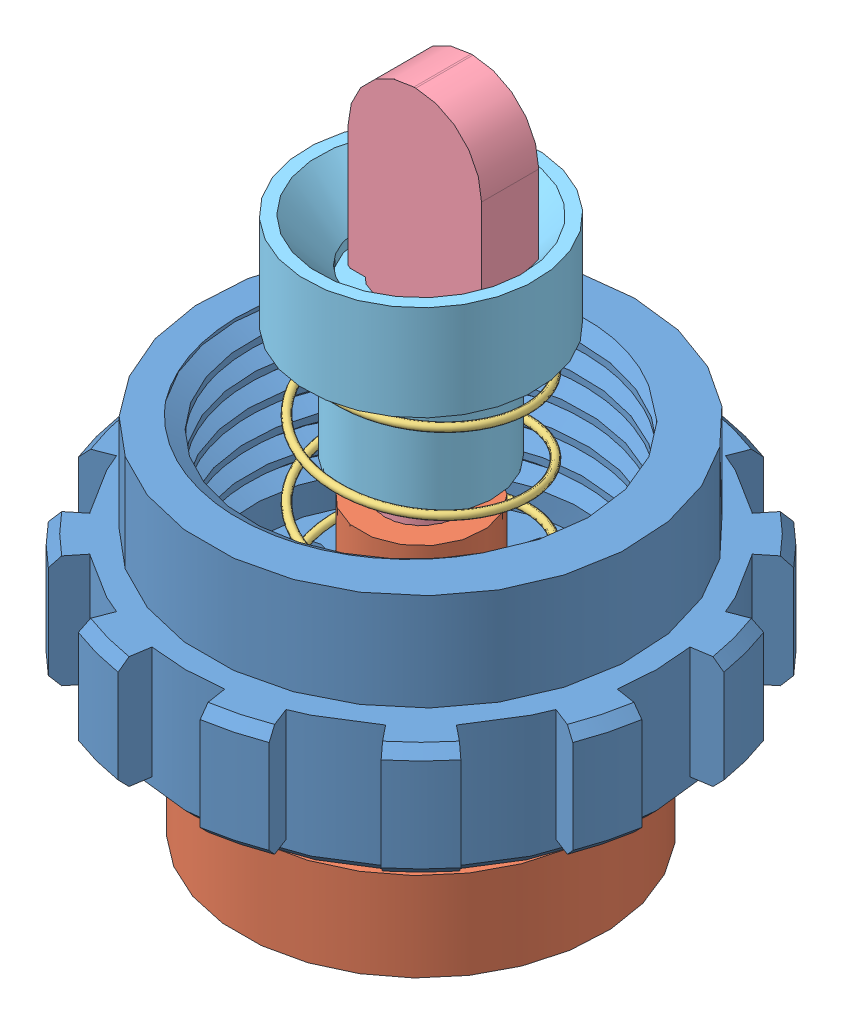
SolidWorks assembly Assy_Pressure_Relief_Valve, configuration Default. Lengths in mm.
Overall size (27.47 35.1 27.47).
5 component instances, 5 part files, 8 mates.
Components (placement in the parent):
- Pressure Relief Valve Body-1: Pressure Relief Valve Body [Default] at origin size (27.47 12.53 27.47)
- Pressure Relief Valve Pop_Up-1: Pressure Relief Valve Pop_Up [Default] at (0 -6.6 0) size (18.9 15.2 18.9)
- Pressure Relief Valve Spring-1: Pressure Relief Valve Spring [Default] at (0 2.3 0) size (10.63 15.06 10.73)
- Pressure Relief Valve Pin Center-1: Pressure Relief Valve Pin Center [Default] at (0 3.6 0) size (7.5 24.9 5.65)
- Pressure Relief Valve Seal-1: Pressure Relief Valve Seal [Default] at (0 10.4 0) x (0.927686 0 -0.373362) z (0.373362 0 0.927686) size (12 11 12)
Mates (geometry in assembly coordinates):
- Concentric1: concentric: cylinder of assembly; cylinder of assembly; cylinder of Pressure Relief Valve Body-1 through (0 -7.7 0) axis (0 1 0) radius 3.5; cylinder of Pressure Relief Valve Pop_Up-1 through (0 -6.6 0) axis (0 -1 0) radius 3.19
- Distance1: distance = 0 mm: plane of assembly; plane of assembly; plane of Pressure Relief Valve Pop_Up-1 through (5.25 0 0) normal (0 1 0); plane of Pressure Relief Valve Body-1 through (0 0 0) normal (0 -1 0)
- Coincident1: coincident: plane of assembly; plane of assembly; plane of Pressure Relief Valve Body-1 through (8.75 2.3 0) normal (0 1 0); plane of Pressure Relief Valve Spring-1 through (0 2.3 0) normal (0 1 0)
- Concentric2: concentric: cylinder of assembly; line of assembly; cylinder of Pressure Relief Valve Pop_Up-1 through (0 -6.6 0) axis (0 -1 0) radius 1.9; line of Pressure Relief Valve Spring-1 through (100 0 52.3) axis (0 0 -1)
- Coincident2: coincident: plane of assembly; plane of assembly; plane of Pressure Relief Valve Pop_Up-1 through (1.9 3.6 0) normal (0 1 0); plane of Pressure Relief Valve Pin Center-1 through (0 3.6 0) normal (0 -1 0)
- Concentric3: concentric: cylinder of assembly; cylinder of assembly; cylinder of Pressure Relief Valve Pop_Up-1 through (0 -6.6 0) axis (0 -1 0) radius 1.9; cylinder of Pressure Relief Valve Pin Center-1 through (0 3.6 0) axis (0 -1 0) radius 1.9
- Concentric4: concentric: cylinder of assembly; cylinder of assembly; cylinder of Pressure Relief Valve Pin Center-1 through (0 3.6 0) axis (0 -1 0) radius 1.9; cylinder of Pressure Relief Valve Seal-1 through (0 10.4 0) axis (0 -1 0) radius 3.8
- Distance2: distance = 0 mm: plane of assembly; line of assembly; plane of Pressure Relief Valve Seal-1 through (3.015 18.6 -1.2134) normal (0 1 0); line of Pressure Relief Valve Pin Center-1 through (2.575 18.6 0.7246) axis (0 0 -1)
